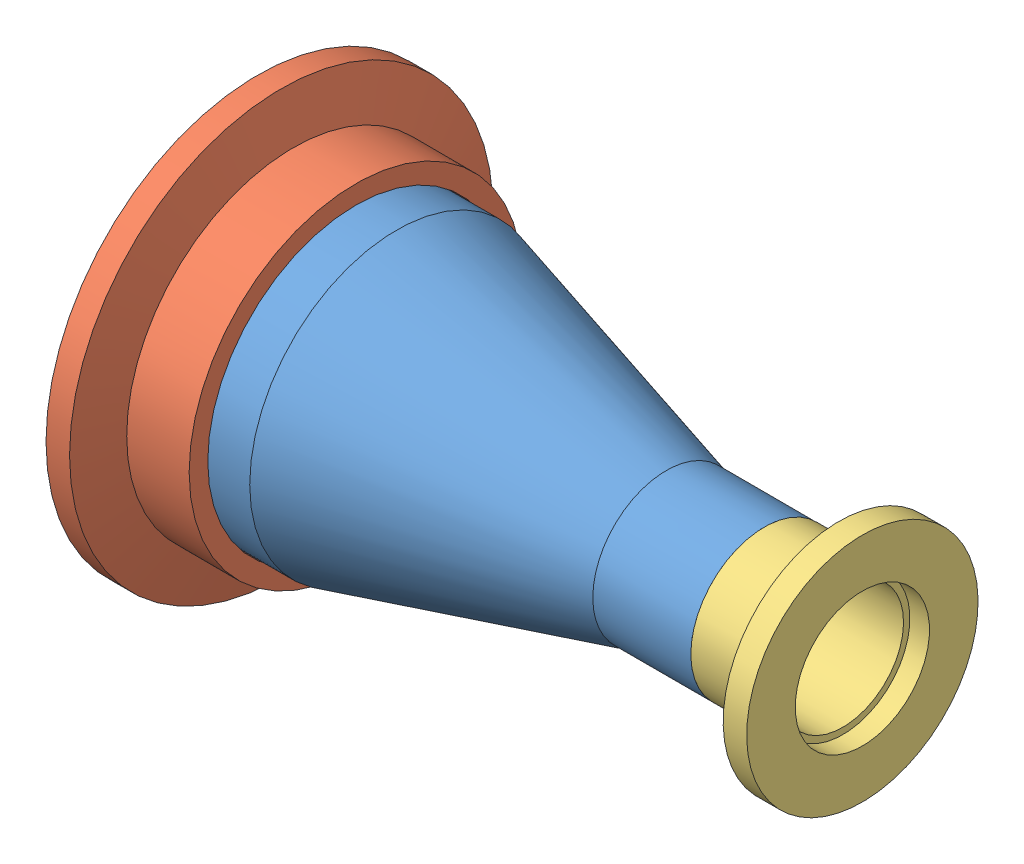
SolidWorks assembly 732007, configuration Default. Lengths in mm.
Overall size (78.33 54.86 54.86).
3 component instances, 3 part files, 4 mates.
Components (placement in the parent):
- 732007-1: 732007 [Default] at (4.8079 31.3657 39.8117) size (60.32 38.1 38.1)
- 713003-1: 713003 [Default] at (-0.5007 31.3657 39.8117) size (12.7 54.86 54.86)
- 715101-1: 715101 [Default] at (77.8329 31.3657 39.8117) x (-1 0 0) z (0 -0.924225 -0.381849) size (12.7 29.97 29.97)
Mates (geometry in assembly coordinates):
- Coincident1: coincident: plane of 732007-1 through (4.8079 31.3657 39.8117) normal (-1 0 0); plane of 713003-1 through (4.8079 50.5427 39.8117) normal (1 0 0)
- Coincident2: coincident: plane of 732007-1 through (65.1329 40.8907 39.8117) normal (1 0 0); plane of 715101-1 through (65.1329 35.0029 31.0085) normal (-1 0 0)
- Concentric1: concentric anti-aligned: cylinder of 732007-1 through (4.8079 31.3657 39.8117) axis (-1 0 0) radius 9.525; cylinder of 715101-1 through (77.8329 31.3657 39.8117) axis (1 0 0) radius 7.874
- Concentric2: concentric aligned: cylinder of 732007-1 through (4.8079 31.3657 39.8117) axis (-1 0 0) radius 19.05; cylinder of 713003-1 through (-0.5007 31.3657 39.8117) axis (-1 0 0) radius 21.59
